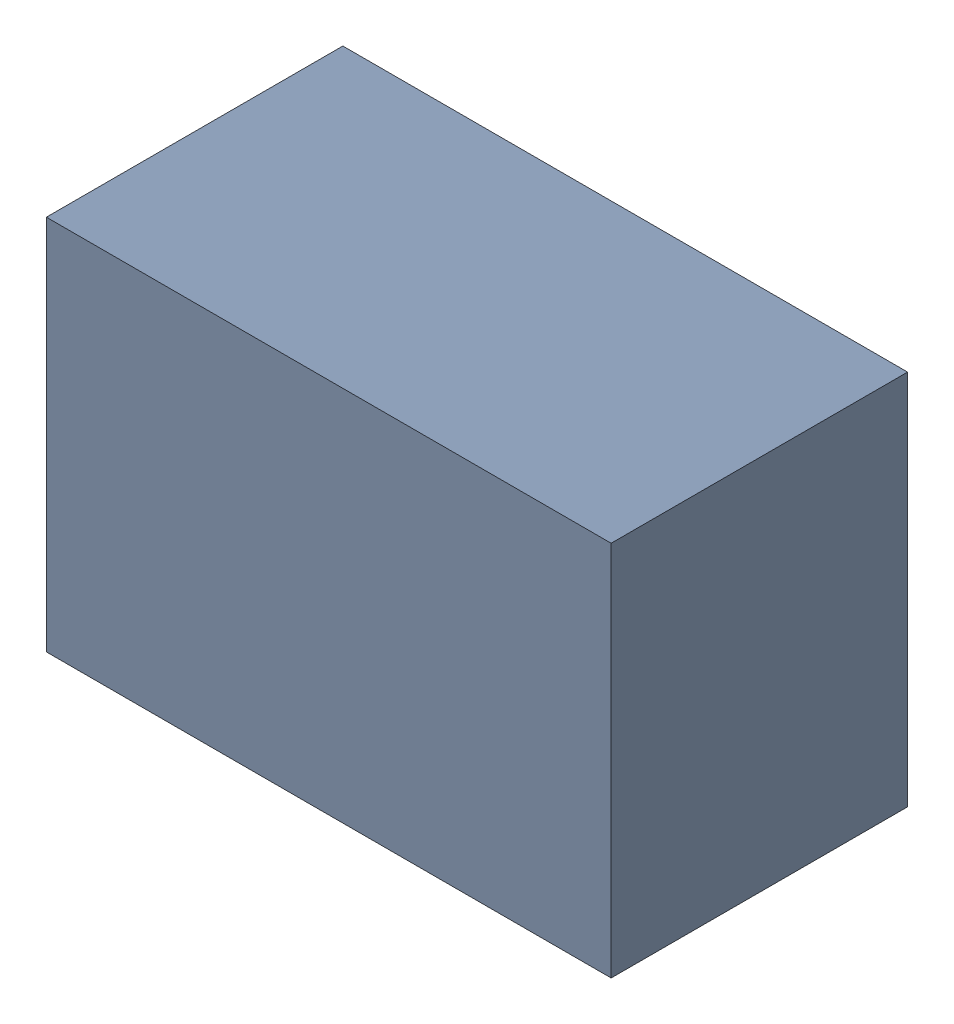
SolidWorks assembly USB01_L2, configuration Default. Lengths in mm.
Overall size (2.29 1.52 1.2).
2 component instances, 1 part files, 0 mates.
Components (placement in the parent):
- 402659088-1: 402659088 [Default] at (156.718 80.772 -2.3024) size (2.29 1.52 1.2)
  - Extruded_28-1: Extruded_28 [Default] at origin size (2.29 1.52 1.2)
